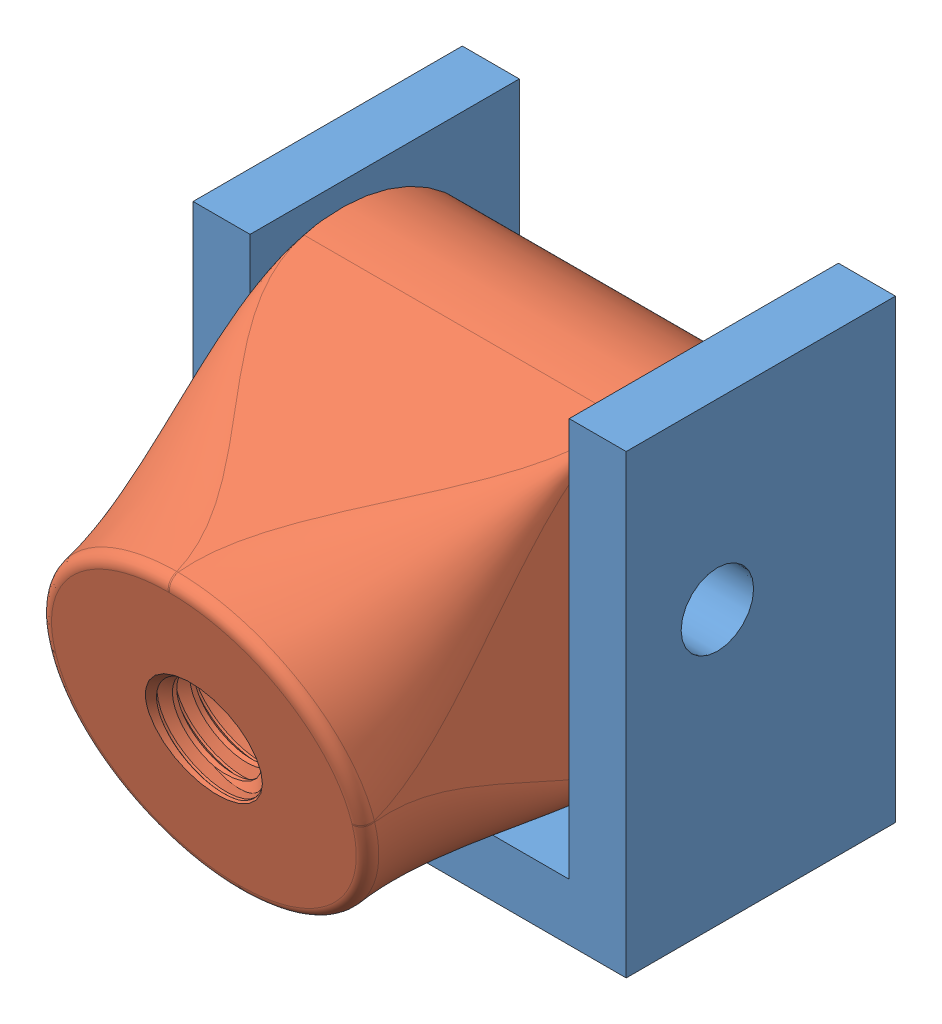
SolidWorks assembly Assem1, configuration Default. Lengths in mm.
Overall size (24.13 26.53 30.27).
2 component instances, 2 part files, 2 mates.
Components (placement in the parent):
- pivot base-1: pivot base [Default] at (-14.2687 -7.7555 -0.4764) size (24.13 25.4 15)
- terminal mount-1: terminal mount [Default] at (-14.2687 7.4845 9.4436) x (1 0 0) z (0 -0.235021 0.97199) size (18.78 18.78 26.6)
Mates (geometry in assembly coordinates):
- Concentric1: concentric aligned: cylinder of pivot base-1 through (-2.2037 7.4845 9.4436) axis (1 0 0) radius 2.0193; cylinder of terminal mount-1 through (-10.4587 7.4845 9.4436) axis (1 0 0) radius 1.5
- Width1: width aligned: plane of terminal mount-1 through (-5.3787 7.4845 9.4436) normal (1 0 0); plane of terminal mount-1 through (-23.1587 7.4845 9.4436) normal (-1 0 0); plane of pivot base-1 through (-23.1587 -7.7555 14.5236) normal (1 0 0); plane of pivot base-1 through (-5.3787 -7.7555 14.5236) normal (-1 0 0)
